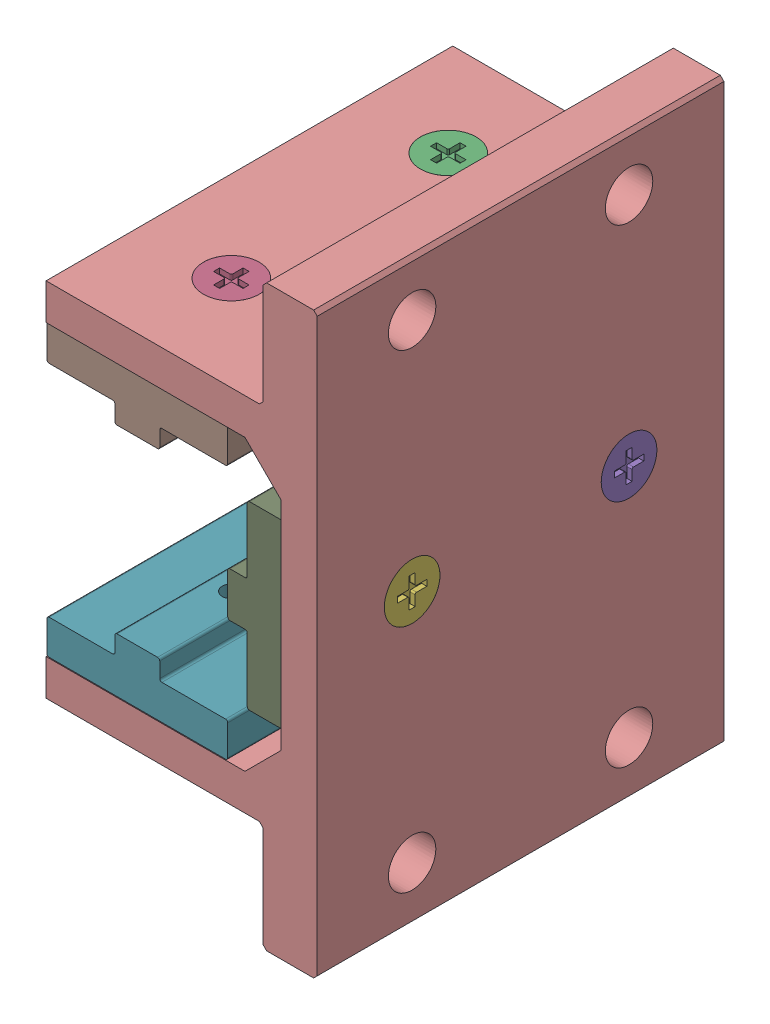
SolidWorks assembly 6825, configuration Default. Lengths in mm.
Overall size (47.62 101.6 71.42).
10 component instances, 3 part files, 0 mates.
Components (placement in the parent):
- 3628_-1: 3628_ [Default] at (0 -29.7892 -19.05) size (9.78 2.08 9.78)
- 3628_-2: 3628_ [Default] at (0 -29.7892 19.05) size (9.78 2.08 9.78)
- 3628_-3: 3628_ [Default] at (0 29.7892 -19.05) x (1 0 0) z (0 0 -1) size (9.78 2.08 9.78)
- 3628_-4: 3628_ [Default] at (0 29.7892 19.05) x (1 0 0) z (0 0 -1) size (9.78 2.08 9.78)
- 3628_-5: 3628_ [Default] at (29.7892 0 -19.05) x (0 0 -1) z (0 1 0) size (9.78 2.08 9.78)
- 3628_-6: 3628_ [Default] at (29.7892 0 19.05) x (0 0 -1) z (0 1 0) size (9.78 2.08 9.78)
- 6825_p2-1: 6825_p2 [Default] at (0 -19.304 0) x (0 -1 0) z (0 0 1) size (9.53 31.75 71.12)
- 6825_p2-2: 6825_p2 [Default] at (0 19.304 0) x (0 1 0) z (0 0 1) size (9.53 31.75 71.12)
- 6825_p2-3: 6825_p2 [Default] at (19.304 0 0) size (9.53 31.75 71.12)
- 6825_p-1: 6825_p [Default] at origin size (47.62 101.6 71.42)
